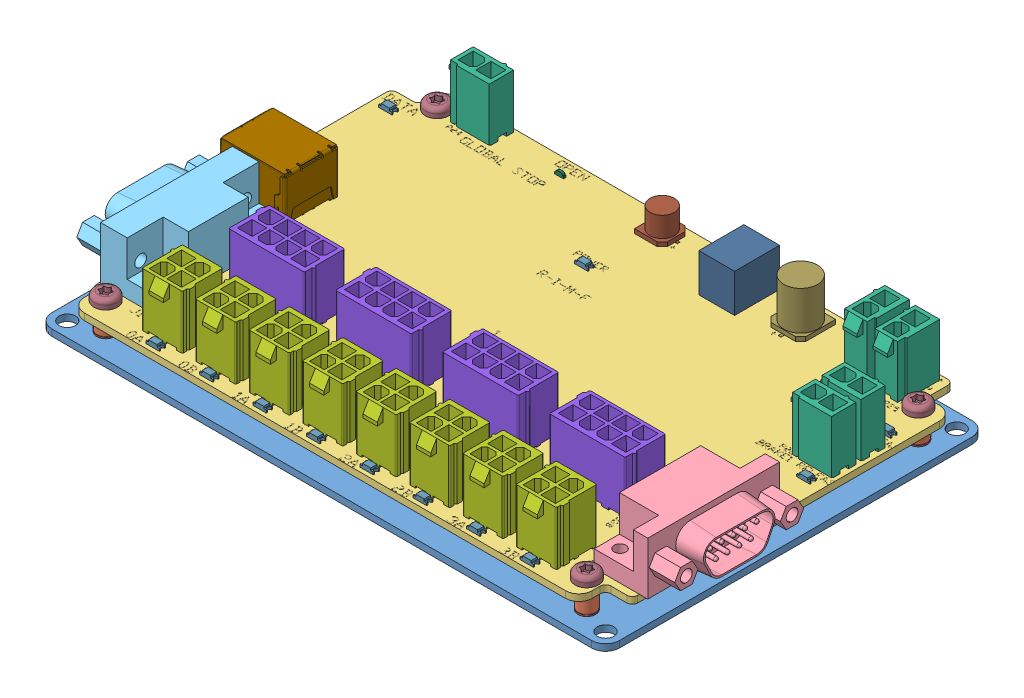
SolidWorks assembly Assem2, configuration Default. Lengths in mm.
Overall size (142.18 63.5 169.36).
54 component instances, 15 part files, 1 mates.
Components (placement in the parent):
- SC4-HUB-1: SC4-HUB [Default] at (-59.6016 56.6477 -77.862) x (1 0 0) z (0 1 0) size (142.18 169.36 63.5)
  - 1107619 Clearpath SC Plate-1: 1107619 Clearpath SC Plate [Default] at (-16.1935 -150.7134 -56.6477) size (134.87 90.42 1.55)
  - 1107622 .25in 4-40 Self Cinching standoff-1: 1107622 .25in 4-40 Self Cinching standoff [Default] at (102.5515 -76.4184 -56.1727) x (0 0 -1) z (0.587223 0.809425 0) size (6.35 5 5.77)
  - 1107622 .25in 4-40 Self Cinching standoff-2: 1107622 .25in 4-40 Self Cinching standoff [Default] at (98.1065 -150.7134 -56.1727) x (0 0 -1) z (1 0 0) size (6.35 5 5.77)
  - 1107622 .25in 4-40 Self Cinching standoff-3: 1107622 .25in 4-40 Self Cinching standoff [Default] at (-16.1935 -150.7134 -56.1727) x (0 0 -1) z (0.718346 -0.695686 0) size (6.35 5 5.77)
  - 1107622 .25in 4-40 Self Cinching standoff-4: 1107622 .25in 4-40 Self Cinching standoff [Default] at (43.9029 -147.9877 -56.1727) x (0 0 -1) z (0.307165 -0.951656 0) size (6.35 5 5.77)
  - 1107622 .25in 4-40 Self Cinching standoff-5: 1107622 .25in 4-40 Self Cinching standoff [Default] at (17.9949 -126.2707 -56.1727) x (0 0 -1) z (0.964551 0.263896 0) size (6.35 5 5.77)
  - 1107622 .25in 4-40 Self Cinching standoff-6: 1107622 .25in 4-40 Self Cinching standoff [Default] at (-16.1935 -71.9734 -56.1727) x (0 0 -1) z (0.97889 -0.204389 0) size (6.35 5 5.77)
  - 1107622 .25in 4-40 Self Cinching standoff-7: 1107622 .25in 4-40 Self Cinching standoff [Default] at (68.8457 -126.2707 -56.1727) x (0 0 -1) z (1 0 0) size (6.35 5 5.77)
  - 1107577 ClearPath SC PWBA-1: 1107577 ClearPath SC PWBA [Default] at (-152.7185 -536.7934 -50.2977) size (133.35 88.9 1.59)
  - DB9RA_M-1: DB9RA_M [Default] at (98.6653 -137.6888 -48.7102) x (0 -1 0) z (-1 0 0) size (31.31 16.05 18.8)
  - DB9RA_F-1: DB9RA_F [Default] at (-9.7419 -137.6628 -48.7102) x (0 -1 0) z (0 0 1) size (31.31 18.41 16.05)
  - 2pin Minifit Vertical Board Mount 039288020-1: 2pin Minifit Vertical Board Mount 039288020 [Default] at (-7.1505 -70.3529 -48.7102) x (0 1 0) z (1 0 0) size (6.2 16.3 11)
  - 2pin Minifit Vertical Board Mount 039288020-2: 2pin Minifit Vertical Board Mount 039288020 [Default] at (101.879 -91.1174 -48.7102) x (0 1 0) z (1 0 0) size (6.2 16.3 11)
  - 2pin Minifit Vertical Board Mount 039288020-3: 2pin Minifit Vertical Board Mount 039288020 [Default] at (101.879 -98.1024 -48.7102) x (0 1 0) z (1 0 0) size (6.2 16.3 11)
  - 2pin Minifit Vertical Board Mount 039288020-4: 2pin Minifit Vertical Board Mount 039288020 [Default] at (96.1466 -72.8467 -48.9942) x (-1 0 0) z (0 1 0) size (6.2 16.3 11)
  - 2pin Minifit Vertical Board Mount 039288020-5: 2pin Minifit Vertical Board Mount 039288020 [Default] at (88.739 -72.6429 -48.7102) x (-1 0 0) z (0 1 0) size (6.2 16.3 11)
  - 4pin minifit-1: 4pin minifit [Default] at (-0.9479 -147.7389 -48.7102) x (1 0 0) z (0 -1 0) size (10.4 16.3 11)
  - 8 pin minifit-1: 8 pin minifit [Default] at (81.583 -129.2921 -48.7102) x (-1 0 0) z (0 1 0) size (21.06 18.32 12.94)
  - 4pin minifit-2: 4pin minifit [Default] at (11.7521 -147.7389 -48.7102) x (1 0 0) z (0 -1 0) size (10.4 16.3 11)
  - 4pin minifit-3: 4pin minifit [Default] at (24.4521 -147.7389 -48.7102) x (1 0 0) z (0 -1 0) size (10.4 16.3 11)
  - 4pin minifit-4: 4pin minifit [Default] at (87.9521 -147.8024 -48.7102) x (1 0 0) z (0 -1 0) size (10.4 16.3 11)
  - 4pin minifit-5: 4pin minifit [Default] at (62.5521 -147.7389 -48.7102) x (1 0 0) z (0 -1 0) size (10.4 16.3 11)
  - 4pin minifit-6: 4pin minifit [Default] at (37.1521 -147.7389 -48.7102) x (1 0 0) z (0 -1 0) size (10.4 16.3 11)
  - 4pin minifit-7: 4pin minifit [Default] at (49.8521 -147.7389 -48.7102) x (1 0 0) z (0 -1 0) size (10.4 16.3 11)
  - 4pin minifit-8: 4pin minifit [Default] at (75.2521 -147.7389 -48.7102) x (1 0 0) z (0 -1 0) size (10.4 16.3 11)
  - 8 pin minifit-2: 8 pin minifit [Default] at (56.183 -129.2921 -48.7102) x (-1 0 0) z (0 1 0) size (21.06 18.32 12.94)
  - 8 pin minifit-3: 8 pin minifit [Default] at (30.783 -129.2921 -48.7102) x (-1 0 0) z (0 1 0) size (21.06 18.32 12.94)
  - 8 pin minifit-4: 8 pin minifit [Default] at (5.383 -129.2921 -48.7102) x (-1 0 0) z (0 1 0) size (21.06 18.32 12.94)
  - 1103187 FCI 61729-0010BLF USB Connector-1: 1103187 FCI 61729-0010BLF USB Connector [Default] at (-10.1169 -108.3624 -48.7102) x (0 1 0) z (1 0 0) size (13.12 13.8 15.94)
  - Blue tx-1: Blue tx [Default] at (57.3395 -73.7514 -48.7102) x (0 1 0) z (1 0 0) size (11.71 12.1 8.5)
  - chip electrolytic_CAP-VA-D-1: chip electrolytic_CAP-VA-D [Default] at (36.1305 -70.8304 -48.7102) x (0 -1 0) z (-1 0 0) size (6.6 5.8 7.8)
  - chip electrolytic_CAP-VA-F-1: chip electrolytic_CAP-VA-F [Default] at (71.246 -73.0529 -48.7102) x (-1 0 0) z (0 1 0) size (8.3 10.2 10)
  - 1106925 .25 PAN HEAD 4-40 THREAD FORMER_93878A110-1: 1106925 .25 PAN HEAD 4-40 THREAD FORMER_93878A110 [Default] at (-16.1935 -71.9734 -48.7102) size (5.56 5.56 8.38)
  - 1106925 .25 PAN HEAD 4-40 THREAD FORMER_93878A110-2: 1106925 .25 PAN HEAD 4-40 THREAD FORMER_93878A110 [Default] at (98.1065 -150.7134 -48.7102) size (5.56 5.56 8.38)
  - 1106925 .25 PAN HEAD 4-40 THREAD FORMER_93878A110-3: 1106925 .25 PAN HEAD 4-40 THREAD FORMER_93878A110 [Default] at (102.5515 -76.4184 -48.7102) size (5.56 5.56 8.38)
  - 1106925 .25 PAN HEAD 4-40 THREAD FORMER_93878A110-4: 1106925 .25 PAN HEAD 4-40 THREAD FORMER_93878A110 [Default] at (-16.1935 -150.7134 -48.7102) size (5.56 5.56 8.38)
  - CMD15-21VGC-1: CMD15-21VGC [Default] at (-0.9479 -154.0509 -48.7102) x (1 0 0) z (0 -1 0) size (3.2 1.1 1.5)
  - CMD15-21VGC-2: CMD15-21VGC [Default] at (11.7521 -154.0509 -48.7102) x (1 0 0) z (0 -1 0) size (3.2 1.1 1.5)
  - CMD15-21VGC-3: CMD15-21VGC [Default] at (24.4521 -154.0509 -48.7102) x (1 0 0) z (0 -1 0) size (3.2 1.1 1.5)
  - CMD15-21VGC-4: CMD15-21VGC [Default] at (37.1521 -154.0509 -48.7102) x (1 0 0) z (0 -1 0) size (3.2 1.1 1.5)
  - CMD15-21VGC-5: CMD15-21VGC [Default] at (49.8521 -154.0509 -48.7102) x (1 0 0) z (0 -1 0) size (3.2 1.1 1.5)
  - CMD15-21VGC-6: CMD15-21VGC [Default] at (62.5521 -154.0509 -48.7102) x (1 0 0) z (0 -1 0) size (3.2 1.1 1.5)
  - CMD15-21VGC-7: CMD15-21VGC [Default] at (75.2521 -154.0509 -48.7102) x (1 0 0) z (0 -1 0) size (3.2 1.1 1.5)
  - CMD15-21VGC-8: CMD15-21VGC [Default] at (87.9521 -154.0509 -48.7102) x (1 0 0) z (0 -1 0) size (3.2 1.1 1.5)
  - CMD15-21VGC-9: CMD15-21VGC [Default] at (5.383 -122.9801 -48.7102) x (1 0 0) z (0 -1 0) size (3.2 1.1 1.5)
  - CMD15-21VGC-10: CMD15-21VGC [Default] at (30.783 -122.9801 -48.7102) x (1 0 0) z (0 -1 0) size (3.2 1.1 1.5)
  - CMD15-21VGC-11: CMD15-21VGC [Default] at (56.183 -122.9801 -48.7102) x (1 0 0) z (0 -1 0) size (3.2 1.1 1.5)
  - CMD15-21VGC-12: CMD15-21VGC [Default] at (81.583 -122.9801 -48.7102) x (1 0 0) z (0 -1 0) size (3.2 1.1 1.5)
  - CMD15-21VGC-13: CMD15-21VGC [Default] at (103.68 -104.1227 -48.8055) x (1 0 0) z (0 -1 0) size (3.2 1.1 1.5)
  - CMD15-21VGC-14: CMD15-21VGC [Default] at (103.8375 -85.1059 -48.7102) x (1 0 0) z (0 -1 0) size (3.2 1.1 1.5)
  - CMD15-21VGC-15: CMD15-21VGC [Default] at (-21.9245 -77.8031 -48.7102) x (1 0 0) z (0 -1 0) size (3.2 1.1 1.5)
  - CMD15-21VGC-16: CMD15-21VGC [Default] at (33.4795 -86.6934 -48.7102) x (1 0 0) z (0 -1 0) size (3.2 1.1 1.5)
  - PG1113F-1: PG1113F [Default] at (12.1085 -71.0304 -48.7318) x (1 0 0) z (0 -1 0) size (2.1 1 0.6)
Mates (geometry in assembly coordinates):
- Coincident1: coincident anti-aligned: plane of SC4-HUB-1/1107619 Clearpath SC Plate-1 through (-82.7547 0 -8.4033) normal (0 -1 0); plane of assembly through (0 0 0) normal (0 1 0)
